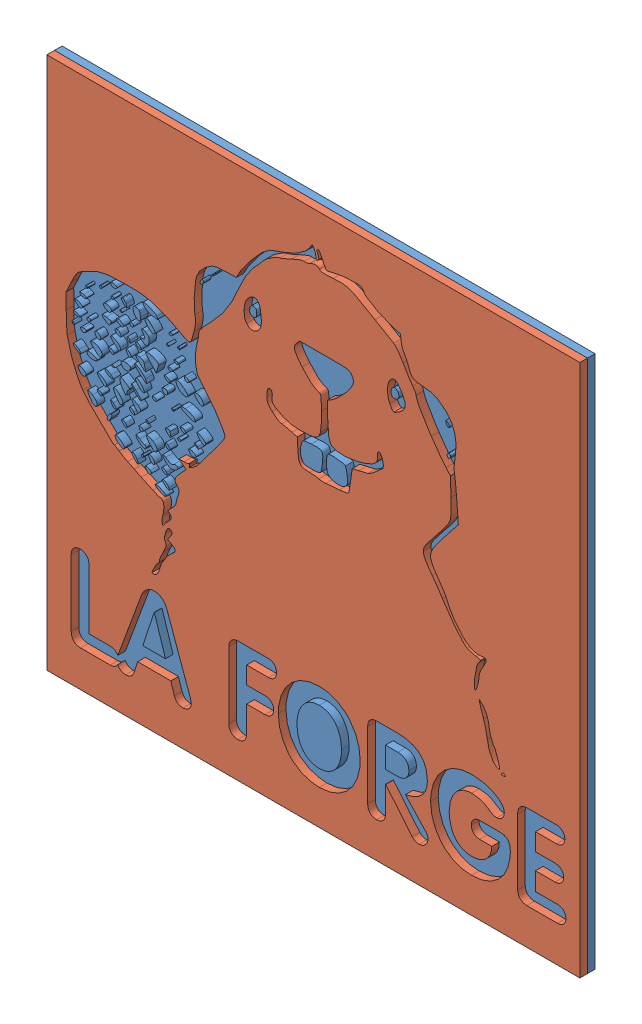
SolidWorks assembly etiquette-forge, configuration Défaut. Lengths in mm.
Overall size (35 35 4).
2 component instances, 2 part files, 3 mates.
Components (placement in the parent):
- etiquette-forge-1-1: etiquette-forge-1 [Défaut] at (-12.444 16.3867 36.001) size (35 35 4)
- etiquette-forge-2-1: etiquette-forge-2 [Défaut] at (-12.444 16.3867 36.501) size (35 35 0.5)
Mates (geometry in assembly coordinates):
- Coïncidente1: coincident anti-aligned: plane of etiquette-forge-1-1 through (-12.444 16.3867 36.501) normal (0 0 1); plane of etiquette-forge-2-1 through (-12.444 16.3867 36.501) normal (0 0 -1)
- Coïncidente2: coincident aligned: plane of etiquette-forge-1-1 through (22.556 16.3867 36.501) normal (1 0 0); plane of etiquette-forge-2-1 through (22.556 16.3867 37.001) normal (1 0 0)
- Coïncidente3: coincident aligned: plane of etiquette-forge-1-1 through (-12.444 16.3867 36.501) normal (0 1 0); plane of etiquette-forge-2-1 through (-12.444 16.3867 37.001) normal (0 1 0)
